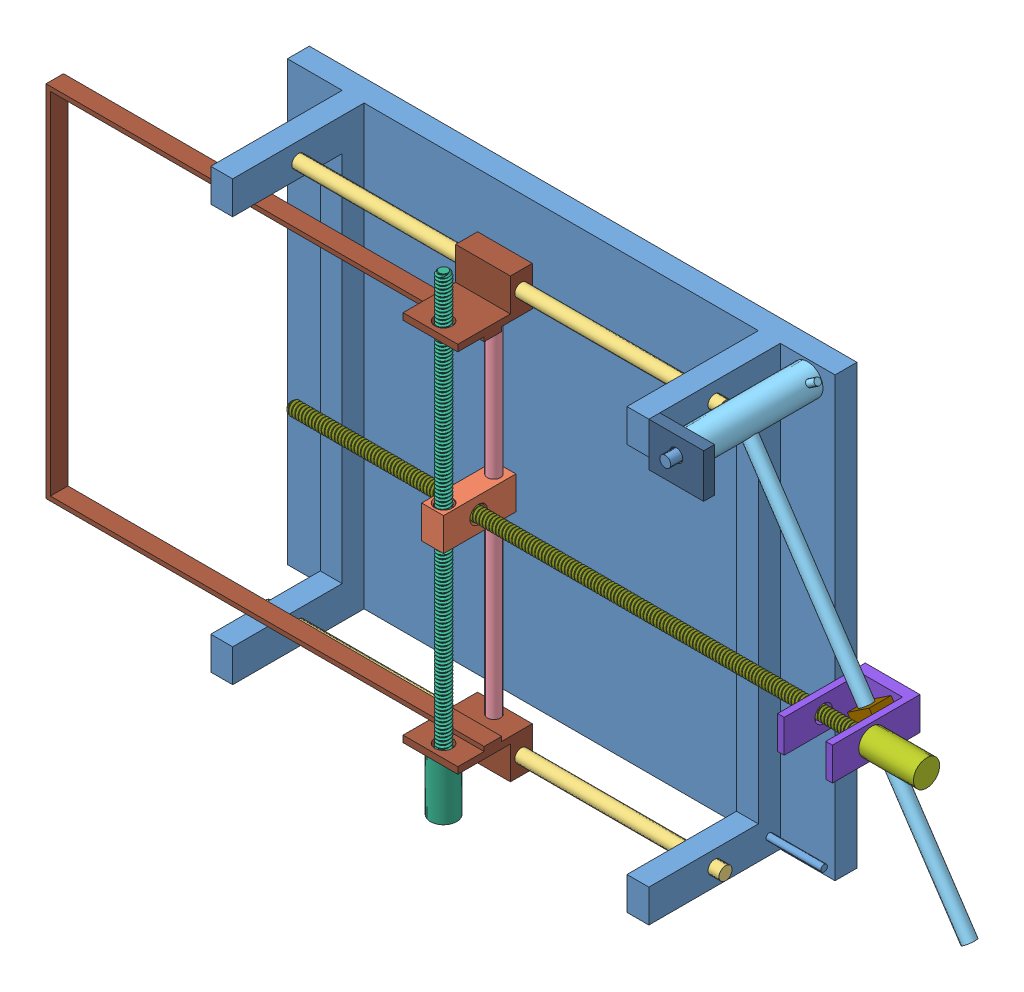
SolidWorks assembly vsa_ut, configuration Défaut. Lengths in mm.
Overall size (414.14 216.44 75).
12 component instances, 11 part files, 27 mates.
Components (placement in the parent):
- base_ut-1: base_ut [Défaut] at (-94.16 45.2956 200) size (250 200 75)
- milieu-1: milieu [Défaut] at (35.1286 -41.6884 268) x (0 -1 0) z (-1 0 0) size (15.74 33 10.38)
- barre1-1: barre1 [Défaut] at (-74.16 -146.7044 240) x (0 -1 0) z (0 0 1) size (6 210 6)
- barre1-2: barre1 [Défaut] at (-74.16 37.2956 240) x (0 0.898626 0.438716) z (0 0.438716 -0.898626) size (6 210 6)
- barre2-1: barre2 [Défaut] at (30.1286 31.2956 240) x (0.563139 0 -0.826362) z (0 -1 0) size (6 6 172)
- cylindre-1: cylindre [Défaut] at (143.34 37.2956 265) x (0.555432 -0.831562 0) z (-0.831562 -0.555432 0) size (194 55 23)
- filetage1-1: filetage1 [Défaut] at (30.1286 -164.7044 263) x (0.888678 0 -0.458532) z (0 1 0) size (12 12 216.44)
- filetage2-1: filetage2 [Défaut] at (239.6188 -49.1884 252) x (0 -0.984109 -0.177566) z (-1 0 0) size (12 12 291.89)
- haut2-1: haut2 [Défaut] at (214.6188 -56.6884 270) x (-1 0 0) z (0 1 0) size (25 40 15)
- haut3-1: haut3 [Défaut] at (211.9748 -51.9577 245) x (-0.831562 -0.555432 0) z (-0.555432 0.831562 0) size (12 10 10)
- haut4-1: haut4 [Défaut] at (155.84 45.2956 270) x (0 -1 0) z (-1 0 0) size (20 5 25)
- fusion_haut-1: fusion_haut [Défaut] at (42.6286 -123.0673 256.4387) x (0 1 0) z (1 0 0) size (200 34 200)
Mates (geometry in assembly coordinates):
- Coaxiale16: concentric anti-aligned: cylinder of base_ut-1 through (-94.16 37.2956 240) axis (1 0 0) radius 3; cylinder of barre1-2 through (135.84 37.2956 240) axis (-1 0 0) radius 3
- Distance1: distance = 5 mm aligned: plane of barre1-2 through (135.84 37.2956 240) normal (1 0 0); plane of base_ut-1 through (130.84 45.2956 270) normal (1 0 0)
- Coaxiale2: concentric anti-aligned: cylinder of base_ut-1 through (-94.16 -146.7044 240) axis (1 0 0) radius 3; cylinder of barre1-1 through (135.84 -146.7044 240) axis (-1 0 0) radius 3
- Distance3: distance = 5 mm aligned: plane of base_ut-1 through (130.84 45.2956 270) normal (1 0 0); plane of barre1-1 through (135.84 -146.7044 240) normal (1 0 0)
- Coaxiale3: concentric anti-aligned: cylinder of base_ut-1 through (143.34 37.2956 275) axis (0 0 -1) radius 2.5; cylinder of cylindre-1 through (143.34 37.2956 210) axis (0 0 1) radius 2.5
- Coïncidente5: coincident anti-aligned: plane of base_ut-1 through (-94.16 45.2956 210) normal (0 0 1); plane of cylindre-1 through (147.228 31.4747 210) normal (0 0 -1)
- Coaxiale4: concentric anti-aligned: cylinder of base_ut-1 through (143.34 37.2956 275) axis (0 0 -1) radius 2.5; cylinder of haut4-1 through (143.34 37.2956 265) axis (0 0 1) radius 3
- Coïncidente8: coincident anti-aligned: plane of base_ut-1 through (130.84 45.2956 270) normal (1 0 0); plane of haut4-1 through (130.84 45.2956 270) normal (-1 0 0)
- Coïncidente9: coincident anti-aligned: plane of cylindre-1 through (143.34 37.2956 265) normal (0 0 1); plane of haut4-1 through (130.84 45.2956 265) normal (0 0 -1)
- Coaxiale5: concentric anti-aligned: cylinder of barre1-1 through (135.84 -146.7044 240) axis (-1 0 0) radius 3; cylinder of fusion_haut-1 through (17.6286 -146.7044 240) axis (1 0 0) radius 3
- Coaxiale6: concentric aligned: cylinder of barre1-2 through (135.84 37.2956 240) axis (-1 0 0) radius 3; cylinder of fusion_haut-1 through (42.6286 37.2956 240) axis (-1 0 0) radius 3
- Coaxiale7: concentric anti-aligned: cylinder of haut2-1 through (207.1188 -49.1884 245) axis (0 0 -1) radius 1; cylinder of haut3-1 through (207.1188 -49.1884 235) axis (0 0 1) radius 1
- Coïncidente10: coincident anti-aligned: plane of haut2-1 through (211.6188 -41.6884 235) normal (0 0 1); plane of haut3-1 through (206.4205 -43.6421 235) normal (0 0 -1)
- Coaxiale8: concentric anti-aligned: cylinder of cylindre-1 through (133.143 52.562 240) axis (-0.555432 0.831562 0) radius 3; cylinder of haut3-1 through (200.1838 -47.8078 240) axis (0.555432 -0.831562 0) radius 3
- Coaxiale9: concentric anti-aligned: circle of milieu-1; cylinder of fusion_haut-1 through (30.1286 45.2956 263) axis (0 -1 0) radius 4
- Coaxiale10: concentric aligned: cylinder of milieu-1 through (30.1286 -41.6884 240) axis (0 -1 0) radius 3; cylinder of fusion_haut-1 through (30.1286 31.2956 240) axis (0 -1 0) radius 3
- Coaxiale11: concentric anti-aligned: cylinder of milieu-1 through (30.1286 -41.6884 240) axis (0 -1 0) radius 3; cylinder of barre2-1 through (30.1286 -140.7044 240) axis (0 1 0) radius 3
- Coïncidente12: coincident anti-aligned: plane of barre2-1 through (30.1286 -140.7044 240) normal (0 -1 0); plane of fusion_haut-1 through (30.1286 -140.7044 240) normal (0 1 0)
- Coïncidente13: coincident anti-aligned: plane of filetage1-1 through (30.1286 -139.7044 263) normal (0 1 0); plane of fusion_haut-1 through (17.6286 -139.7044 269) normal (0 -1 0)
- Coaxiale14: concentric anti-aligned: cone of milieu-1 through (34.1286 -49.1884 252) axis (-1 0 0); cylinder of haut2-1 through (189.6188 -49.1884 252) axis (1 0 0) radius 4
- Hélicoïdale4: screw = 1 aligned: cylinder of milieu-1 through (30.1286 -41.6884 263) axis (0 -1 0) radius 3; cylinder of filetage1-1 through (30.1286 50.2956 263) axis (0 -1 0) radius 3
- Hélicoïdale6: screw = 1 anti-aligned: cone of milieu-1 through (34.1286 -49.1884 252) axis (-1 0 0); cylinder of filetage2-1 through (-50.3812 -49.1884 252) axis (1 0 0) radius 3
- Largeur1: width anti-aligned: plane of fusion_haut-1 through (-155.3714 25.2956 257) normal (0 -1 0); plane of fusion_haut-1 through (-155.3714 -134.7044 257) normal (0 1 0); plane of milieu-1 through (25.1286 -41.6884 268) normal (0 1 0); plane of milieu-1 through (25.1286 -56.6884 268) normal (0 -1 0)
- Largeur2: width anti-aligned: plane of base_ut-1 through (-59.16 45.2956 270) normal (1 0 0); plane of base_ut-1 through (120.84 45.2956 270) normal (-1 0 0); plane of fusion_haut-1 through (17.6286 -154.7044 269) normal (-1 0 0); plane of fusion_haut-1 through (42.6286 27.2956 257) normal (1 0 0)
- Coïncidente16: coincident anti-aligned: plane of filetage2-1 through (214.6188 -49.1884 252) normal (-1 0 0); plane of haut2-1 through (214.6188 -41.6884 270) normal (1 0 0)
- Verrouiller3: lock: unknown of milieu-1; unknown of filetage2-1
- Verrouiller4: lock: unknown of milieu-1; unknown of filetage1-1
